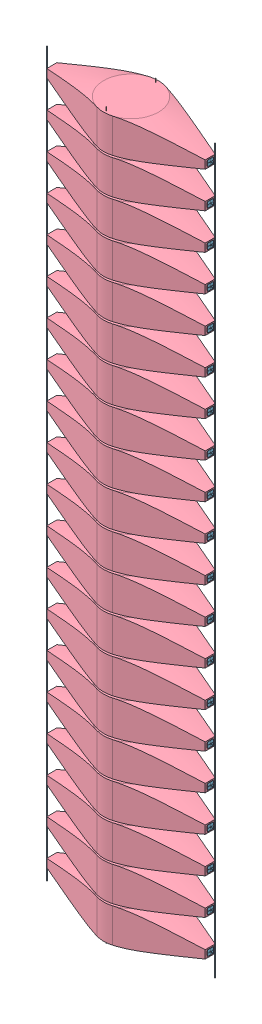
SolidWorks assembly String-20, configuration 默认. Lengths in mm.
Overall size (350.8 1510.25 116.67).
140 component instances, 5 part files, 0 mates.
Components (placement in the parent):
- Unit-1: Unit [默认] at (24.7158 5.5651 269.4655) size (350.8 85.25 116.67)
  - BEGeDet-1: BEGeDet [默认] at (-1.1221 -39.076 80) size (80 40 80)
  - InnerShell-3: InnerShell [默认] at (-1.1221 11.4233 80) x (-1 0 0) z (0 0 1) size (102 61 102)
  - Electronics-1: Electronics [默认] at (-1.1221 -49.676 80) size (21.21 85 103.7)
  - OuterShell-2: OuterShell [默认] at (-1.1221 -55.5767 80) size (330 72.56 116.67)
  - SiPMArray-4: SiPMArray [默认] at (163.8779 -19.9292 80) size (10.4 81 12)
  - SiPMArray-6: SiPMArray [默认] at (-166.1221 -19.9292 80) x (-1 0 0) z (0 0 -1) size (10.4 81 12)
- Unit-2: Unit [默认] at (24.7158 80.5651 269.4655) size (350.8 85.25 116.67)
  - BEGeDet-1: BEGeDet [默认] at (-1.1221 -39.076 80) size (80 40 80)
  - InnerShell-3: InnerShell [默认] at (-1.1221 11.4233 80) x (-1 0 0) z (0 0 1) size (102 61 102)
  - Electronics-1: Electronics [默认] at (-1.1221 -49.676 80) size (21.21 85 103.7)
  - OuterShell-2: OuterShell [默认] at (-1.1221 -55.5767 80) size (330 72.56 116.67)
  - SiPMArray-4: SiPMArray [默认] at (163.8779 -19.9292 80) size (10.4 81 12)
  - SiPMArray-6: SiPMArray [默认] at (-166.1221 -19.9292 80) x (-1 0 0) z (0 0 -1) size (10.4 81 12)
- Unit-3: Unit [默认] at (24.7158 155.5651 269.4655) size (350.8 85.25 116.67)
  - BEGeDet-1: BEGeDet [默认] at (-1.1221 -39.076 80) size (80 40 80)
  - InnerShell-3: InnerShell [默认] at (-1.1221 11.4233 80) x (-1 0 0) z (0 0 1) size (102 61 102)
  - Electronics-1: Electronics [默认] at (-1.1221 -49.676 80) size (21.21 85 103.7)
  - OuterShell-2: OuterShell [默认] at (-1.1221 -55.5767 80) size (330 72.56 116.67)
  - SiPMArray-4: SiPMArray [默认] at (163.8779 -19.9292 80) size (10.4 81 12)
  - SiPMArray-6: SiPMArray [默认] at (-166.1221 -19.9292 80) x (-1 0 0) z (0 0 -1) size (10.4 81 12)
- Unit-4: Unit [默认] at (24.7158 230.5651 269.4655) size (350.8 85.25 116.67)
  - BEGeDet-1: BEGeDet [默认] at (-1.1221 -39.076 80) size (80 40 80)
  - InnerShell-3: InnerShell [默认] at (-1.1221 11.4233 80) x (-1 0 0) z (0 0 1) size (102 61 102)
  - Electronics-1: Electronics [默认] at (-1.1221 -49.676 80) size (21.21 85 103.7)
  - OuterShell-2: OuterShell [默认] at (-1.1221 -55.5767 80) size (330 72.56 116.67)
  - SiPMArray-4: SiPMArray [默认] at (163.8779 -19.9292 80) size (10.4 81 12)
  - SiPMArray-6: SiPMArray [默认] at (-166.1221 -19.9292 80) x (-1 0 0) z (0 0 -1) size (10.4 81 12)
- Unit-5: Unit [默认] at (24.7158 305.5651 269.4655) size (350.8 85.25 116.67)
  - BEGeDet-1: BEGeDet [默认] at (-1.1221 -39.076 80) size (80 40 80)
  - InnerShell-3: InnerShell [默认] at (-1.1221 11.4233 80) x (-1 0 0) z (0 0 1) size (102 61 102)
  - Electronics-1: Electronics [默认] at (-1.1221 -49.676 80) size (21.21 85 103.7)
  - OuterShell-2: OuterShell [默认] at (-1.1221 -55.5767 80) size (330 72.56 116.67)
  - SiPMArray-4: SiPMArray [默认] at (163.8779 -19.9292 80) size (10.4 81 12)
  - SiPMArray-6: SiPMArray [默认] at (-166.1221 -19.9292 80) x (-1 0 0) z (0 0 -1) size (10.4 81 12)
- Unit-6: Unit [默认] at (24.7158 380.5651 269.4655) size (350.8 85.25 116.67)
  - BEGeDet-1: BEGeDet [默认] at (-1.1221 -39.076 80) size (80 40 80)
  - InnerShell-3: InnerShell [默认] at (-1.1221 11.4233 80) x (-1 0 0) z (0 0 1) size (102 61 102)
  - Electronics-1: Electronics [默认] at (-1.1221 -49.676 80) size (21.21 85 103.7)
  - OuterShell-2: OuterShell [默认] at (-1.1221 -55.5767 80) size (330 72.56 116.67)
  - SiPMArray-4: SiPMArray [默认] at (163.8779 -19.9292 80) size (10.4 81 12)
  - SiPMArray-6: SiPMArray [默认] at (-166.1221 -19.9292 80) x (-1 0 0) z (0 0 -1) size (10.4 81 12)
- Unit-7: Unit [默认] at (24.7158 455.5651 269.4655) size (350.8 85.25 116.67)
  - BEGeDet-1: BEGeDet [默认] at (-1.1221 -39.076 80) size (80 40 80)
  - InnerShell-3: InnerShell [默认] at (-1.1221 11.4233 80) x (-1 0 0) z (0 0 1) size (102 61 102)
  - Electronics-1: Electronics [默认] at (-1.1221 -49.676 80) size (21.21 85 103.7)
  - OuterShell-2: OuterShell [默认] at (-1.1221 -55.5767 80) size (330 72.56 116.67)
  - SiPMArray-4: SiPMArray [默认] at (163.8779 -19.9292 80) size (10.4 81 12)
  - SiPMArray-6: SiPMArray [默认] at (-166.1221 -19.9292 80) x (-1 0 0) z (0 0 -1) size (10.4 81 12)
- Unit-8: Unit [默认] at (24.7158 530.5651 269.4655) size (350.8 85.25 116.67)
  - BEGeDet-1: BEGeDet [默认] at (-1.1221 -39.076 80) size (80 40 80)
  - InnerShell-3: InnerShell [默认] at (-1.1221 11.4233 80) x (-1 0 0) z (0 0 1) size (102 61 102)
  - Electronics-1: Electronics [默认] at (-1.1221 -49.676 80) size (21.21 85 103.7)
  - OuterShell-2: OuterShell [默认] at (-1.1221 -55.5767 80) size (330 72.56 116.67)
  - SiPMArray-4: SiPMArray [默认] at (163.8779 -19.9292 80) size (10.4 81 12)
  - SiPMArray-6: SiPMArray [默认] at (-166.1221 -19.9292 80) x (-1 0 0) z (0 0 -1) size (10.4 81 12)
- Unit-9: Unit [默认] at (24.7158 605.5651 269.4655) size (350.8 85.25 116.67)
  - BEGeDet-1: BEGeDet [默认] at (-1.1221 -39.076 80) size (80 40 80)
  - InnerShell-3: InnerShell [默认] at (-1.1221 11.4233 80) x (-1 0 0) z (0 0 1) size (102 61 102)
  - Electronics-1: Electronics [默认] at (-1.1221 -49.676 80) size (21.21 85 103.7)
  - OuterShell-2: OuterShell [默认] at (-1.1221 -55.5767 80) size (330 72.56 116.67)
  - SiPMArray-4: SiPMArray [默认] at (163.8779 -19.9292 80) size (10.4 81 12)
  - SiPMArray-6: SiPMArray [默认] at (-166.1221 -19.9292 80) x (-1 0 0) z (0 0 -1) size (10.4 81 12)
- Unit-10: Unit [默认] at (24.7158 680.5651 269.4655) size (350.8 85.25 116.67)
  - BEGeDet-1: BEGeDet [默认] at (-1.1221 -39.076 80) size (80 40 80)
  - InnerShell-3: InnerShell [默认] at (-1.1221 11.4233 80) x (-1 0 0) z (0 0 1) size (102 61 102)
  - Electronics-1: Electronics [默认] at (-1.1221 -49.676 80) size (21.21 85 103.7)
  - OuterShell-2: OuterShell [默认] at (-1.1221 -55.5767 80) size (330 72.56 116.67)
  - SiPMArray-4: SiPMArray [默认] at (163.8779 -19.9292 80) size (10.4 81 12)
  - SiPMArray-6: SiPMArray [默认] at (-166.1221 -19.9292 80) x (-1 0 0) z (0 0 -1) size (10.4 81 12)
- Unit-11: Unit [默认] at (24.7158 755.5651 269.4655) size (350.8 85.25 116.67)
  - BEGeDet-1: BEGeDet [默认] at (-1.1221 -39.076 80) size (80 40 80)
  - InnerShell-3: InnerShell [默认] at (-1.1221 11.4233 80) x (-1 0 0) z (0 0 1) size (102 61 102)
  - Electronics-1: Electronics [默认] at (-1.1221 -49.676 80) size (21.21 85 103.7)
  - OuterShell-2: OuterShell [默认] at (-1.1221 -55.5767 80) size (330 72.56 116.67)
  - SiPMArray-4: SiPMArray [默认] at (163.8779 -19.9292 80) size (10.4 81 12)
  - SiPMArray-6: SiPMArray [默认] at (-166.1221 -19.9292 80) x (-1 0 0) z (0 0 -1) size (10.4 81 12)
- Unit-12: Unit [默认] at (24.7158 830.5651 269.4655) size (350.8 85.25 116.67)
  - BEGeDet-1: BEGeDet [默认] at (-1.1221 -39.076 80) size (80 40 80)
  - InnerShell-3: InnerShell [默认] at (-1.1221 11.4233 80) x (-1 0 0) z (0 0 1) size (102 61 102)
  - Electronics-1: Electronics [默认] at (-1.1221 -49.676 80) size (21.21 85 103.7)
  - OuterShell-2: OuterShell [默认] at (-1.1221 -55.5767 80) size (330 72.56 116.67)
  - SiPMArray-4: SiPMArray [默认] at (163.8779 -19.9292 80) size (10.4 81 12)
  - SiPMArray-6: SiPMArray [默认] at (-166.1221 -19.9292 80) x (-1 0 0) z (0 0 -1) size (10.4 81 12)
- Unit-13: Unit [默认] at (24.7158 905.5651 269.4655) size (350.8 85.25 116.67)
  - BEGeDet-1: BEGeDet [默认] at (-1.1221 -39.076 80) size (80 40 80)
  - InnerShell-3: InnerShell [默认] at (-1.1221 11.4233 80) x (-1 0 0) z (0 0 1) size (102 61 102)
  - Electronics-1: Electronics [默认] at (-1.1221 -49.676 80) size (21.21 85 103.7)
  - OuterShell-2: OuterShell [默认] at (-1.1221 -55.5767 80) size (330 72.56 116.67)
  - SiPMArray-4: SiPMArray [默认] at (163.8779 -19.9292 80) size (10.4 81 12)
  - SiPMArray-6: SiPMArray [默认] at (-166.1221 -19.9292 80) x (-1 0 0) z (0 0 -1) size (10.4 81 12)
- Unit-14: Unit [默认] at (24.7158 980.5651 269.4655) size (350.8 85.25 116.67)
  - BEGeDet-1: BEGeDet [默认] at (-1.1221 -39.076 80) size (80 40 80)
  - InnerShell-3: InnerShell [默认] at (-1.1221 11.4233 80) x (-1 0 0) z (0 0 1) size (102 61 102)
  - Electronics-1: Electronics [默认] at (-1.1221 -49.676 80) size (21.21 85 103.7)
  - OuterShell-2: OuterShell [默认] at (-1.1221 -55.5767 80) size (330 72.56 116.67)
  - SiPMArray-4: SiPMArray [默认] at (163.8779 -19.9292 80) size (10.4 81 12)
  - SiPMArray-6: SiPMArray [默认] at (-166.1221 -19.9292 80) x (-1 0 0) z (0 0 -1) size (10.4 81 12)
- Unit-15: Unit [默认] at (24.7158 1055.5651 269.4655) size (350.8 85.25 116.67)
  - BEGeDet-1: BEGeDet [默认] at (-1.1221 -39.076 80) size (80 40 80)
  - InnerShell-3: InnerShell [默认] at (-1.1221 11.4233 80) x (-1 0 0) z (0 0 1) size (102 61 102)
  - Electronics-1: Electronics [默认] at (-1.1221 -49.676 80) size (21.21 85 103.7)
  - OuterShell-2: OuterShell [默认] at (-1.1221 -55.5767 80) size (330 72.56 116.67)
  - SiPMArray-4: SiPMArray [默认] at (163.8779 -19.9292 80) size (10.4 81 12)
  - SiPMArray-6: SiPMArray [默认] at (-166.1221 -19.9292 80) x (-1 0 0) z (0 0 -1) size (10.4 81 12)
- Unit-16: Unit [默认] at (24.7158 1130.5651 269.4655) size (350.8 85.25 116.67)
  - BEGeDet-1: BEGeDet [默认] at (-1.1221 -39.076 80) size (80 40 80)
  - InnerShell-3: InnerShell [默认] at (-1.1221 11.4233 80) x (-1 0 0) z (0 0 1) size (102 61 102)
  - Electronics-1: Electronics [默认] at (-1.1221 -49.676 80) size (21.21 85 103.7)
  - OuterShell-2: OuterShell [默认] at (-1.1221 -55.5767 80) size (330 72.56 116.67)
  - SiPMArray-4: SiPMArray [默认] at (163.8779 -19.9292 80) size (10.4 81 12)
  - SiPMArray-6: SiPMArray [默认] at (-166.1221 -19.9292 80) x (-1 0 0) z (0 0 -1) size (10.4 81 12)
- Unit-17: Unit [默认] at (24.7158 1205.5651 269.4655) size (350.8 85.25 116.67)
  - BEGeDet-1: BEGeDet [默认] at (-1.1221 -39.076 80) size (80 40 80)
  - InnerShell-3: InnerShell [默认] at (-1.1221 11.4233 80) x (-1 0 0) z (0 0 1) size (102 61 102)
  - Electronics-1: Electronics [默认] at (-1.1221 -49.676 80) size (21.21 85 103.7)
  - OuterShell-2: OuterShell [默认] at (-1.1221 -55.5767 80) size (330 72.56 116.67)
  - SiPMArray-4: SiPMArray [默认] at (163.8779 -19.9292 80) size (10.4 81 12)
  - SiPMArray-6: SiPMArray [默认] at (-166.1221 -19.9292 80) x (-1 0 0) z (0 0 -1) size (10.4 81 12)
- Unit-18: Unit [默认] at (24.7158 1280.5651 269.4655) size (350.8 85.25 116.67)
  - BEGeDet-1: BEGeDet [默认] at (-1.1221 -39.076 80) size (80 40 80)
  - InnerShell-3: InnerShell [默认] at (-1.1221 11.4233 80) x (-1 0 0) z (0 0 1) size (102 61 102)
  - Electronics-1: Electronics [默认] at (-1.1221 -49.676 80) size (21.21 85 103.7)
  - OuterShell-2: OuterShell [默认] at (-1.1221 -55.5767 80) size (330 72.56 116.67)
  - SiPMArray-4: SiPMArray [默认] at (163.8779 -19.9292 80) size (10.4 81 12)
  - SiPMArray-6: SiPMArray [默认] at (-166.1221 -19.9292 80) x (-1 0 0) z (0 0 -1) size (10.4 81 12)
- Unit-19: Unit [默认] at (24.7158 1355.5651 269.4655) size (350.8 85.25 116.67)
  - BEGeDet-1: BEGeDet [默认] at (-1.1221 -39.076 80) size (80 40 80)
  - InnerShell-3: InnerShell [默认] at (-1.1221 11.4233 80) x (-1 0 0) z (0 0 1) size (102 61 102)
  - Electronics-1: Electronics [默认] at (-1.1221 -49.676 80) size (21.21 85 103.7)
  - OuterShell-2: OuterShell [默认] at (-1.1221 -55.5767 80) size (330 72.56 116.67)
  - SiPMArray-4: SiPMArray [默认] at (163.8779 -19.9292 80) size (10.4 81 12)
  - SiPMArray-6: SiPMArray [默认] at (-166.1221 -19.9292 80) x (-1 0 0) z (0 0 -1) size (10.4 81 12)
- Unit-20: Unit [默认] at (24.7158 1430.5651 269.4655) size (350.8 85.25 116.67)
  - BEGeDet-1: BEGeDet [默认] at (-1.1221 -39.076 80) size (80 40 80)
  - InnerShell-3: InnerShell [默认] at (-1.1221 11.4233 80) x (-1 0 0) z (0 0 1) size (102 61 102)
  - Electronics-1: Electronics [默认] at (-1.1221 -49.676 80) size (21.21 85 103.7)
  - OuterShell-2: OuterShell [默认] at (-1.1221 -55.5767 80) size (330 72.56 116.67)
  - SiPMArray-4: SiPMArray [默认] at (163.8779 -19.9292 80) size (10.4 81 12)
  - SiPMArray-6: SiPMArray [默认] at (-166.1221 -19.9292 80) x (-1 0 0) z (0 0 -1) size (10.4 81 12)
